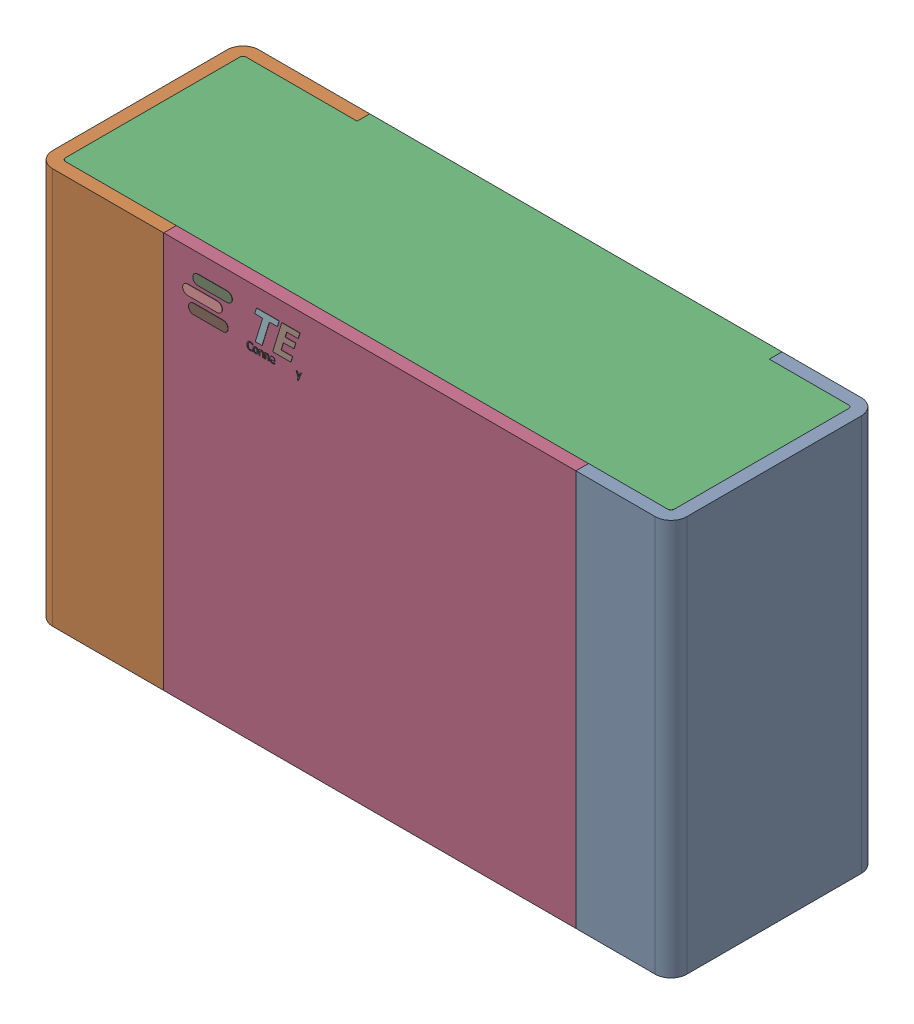
SolidWorks assembly RY.step, configuration Default. Lengths in mm.
Overall size (2 1.25 0.65).
5 component instances, 4 part files, 0 mates.
Components (placement in the parent):
- Res_TE_Connectivity_CPF0805B66R5E1_eec.step-1: Res_TE_Connectivity_CPF0805B66R5E1_eec.step [Default] at (51.169 17.907 0) size (2 1.25 0.65)
  - 1.step-1: 1.step [Default] at origin size (2 1.25 0.65)
  - 2.step-1: 2.step [Default] at origin size (1.92 1.25 0.61)
  - 3.step-1: 3.step [Default] at origin size (1.3 1.25 0.04)
  - TE connectivity Logo 1 (2).step-1: TE connectivity Logo 1 (2).step [Default] at (5.4285 0.313 0.551) x (-1 0 0) z (0 0 1) size (0.37 0.13 0.11)
